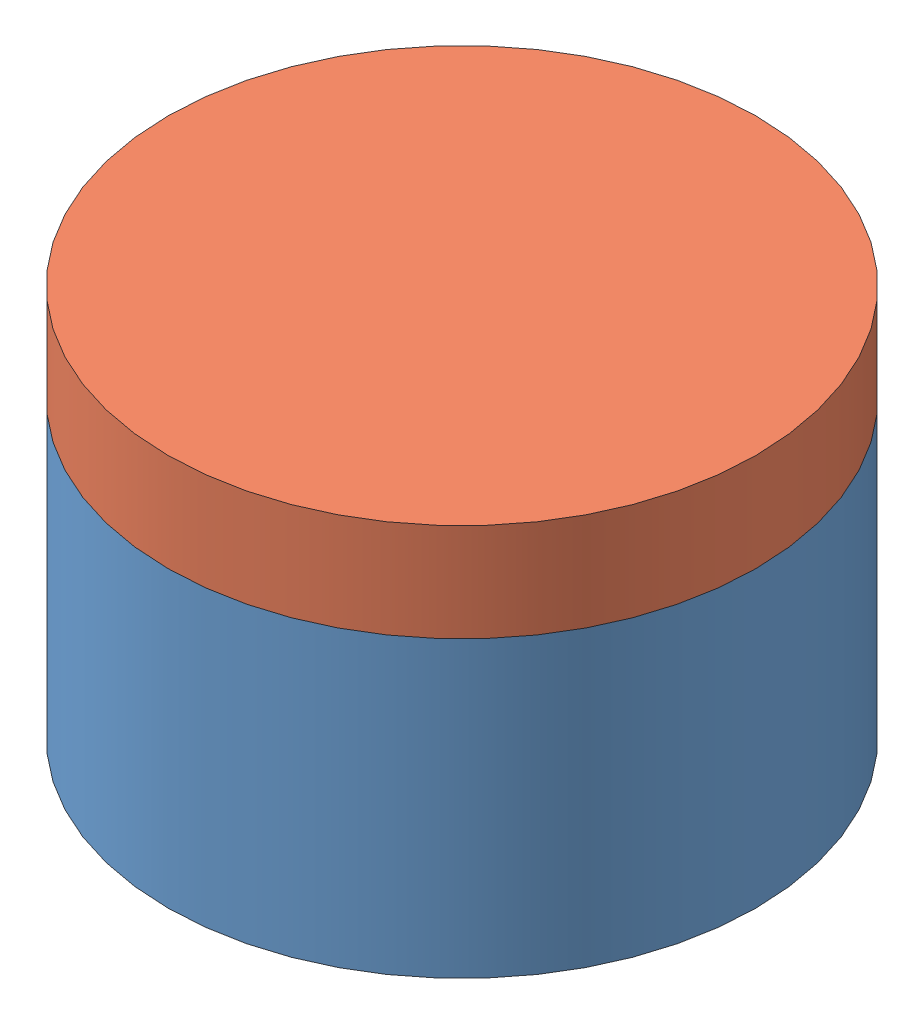
SolidWorks assembly cylinder, configuration Default. Lengths in mm.
Overall size (76.2 50.8 76.2).
2 component instances, 2 part files, 2 mates.
Components (placement in the parent):
- cylinder_bottom-1: cylinder_bottom [Default] at origin size (76.2 38.95 76.2)
- cylinder_top-1: cylinder_top [Default] at (0 50.8 0) x (-1 0 0) z (0 0 1) size (76.2 38.12 76.2)
Mates (geometry in assembly coordinates):
- Coincident3: coincident anti-aligned: circle of cylinder_bottom-1; circle of cylinder_top-1
- Concentric2: concentric anti-aligned: circle of cylinder_bottom-1; circle of cylinder_top-1
